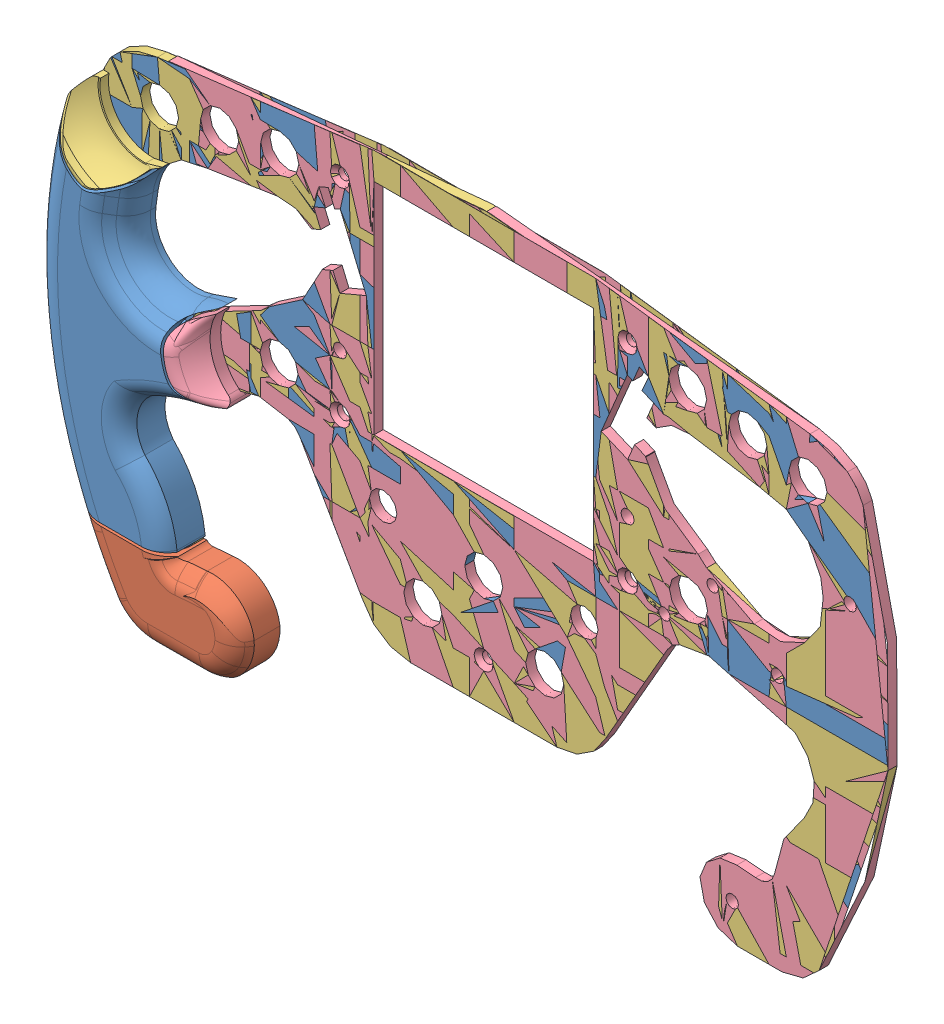
SolidWorks assembly right grip assembly, configuration Default. Lengths in mm.
Overall size (68.83 149.76 15.01).
4 component instances, 4 part files, 9 mates.
Components (placement in the parent):
- left grip no ends or edges-1: left grip no ends or edges [Default] at (82.6904 40.4146 11.7802) size (272.22 167.67 14.17)
- bottom end-1: bottom end [Default] at (82.6904 40.4146 11.7802) size (55.53 45.36 15)
- top end-1: top end [Default] at (82.6904 40.4146 11.7802) size (267.09 167.67 14.23)
- middle end-1: middle end [Default] at (82.6904 40.4146 11.7802) size (236.96 167.67 14.21)
Mates (geometry in assembly coordinates):
- Coincident1: coincident aligned: plane of left grip no ends or edges-1 through (82.6904 40.4146 11.7802) normal (0 0 -1); plane of bottom end-1 through (82.6904 40.4146 11.7802) normal (0 0 -1)
- Coincident2: coincident aligned: plane of left grip no ends or edges-1 through (82.6904 40.4146 11.7802) normal (0 0 -1); plane of top end-1 through (82.6904 40.4146 11.7802) normal (0 0 -1)
- Parallel1: parallel aligned: line of left grip no ends or edges-1 through (-16.1425 -18.1674 25.2802) axis (-1 0 0); line of bottom end-1 through (-16.0263 -19.0674 25.2802) axis (-1 0 0)
- Concentric3: concentric aligned: cylinder of left grip no ends or edges-1 through (116.1065 46.6634 26.7802) axis (0 0 -1) radius 169.0986; cylinder of bottom end-1 through (116.1065 46.6634 26.7802) axis (0 0 -1) radius 169.0986
- Concentric5: concentric aligned: cylinder of left grip no ends or edges-1 through (-16.4419 76.0793 26.7802) axis (0 0 -1) radius 33.4055; cylinder of top end-1 through (-16.4419 76.0793 26.7802) axis (0 0 -1) radius 33.4055
- Concentric6: concentric aligned: cylinder of left grip no ends or edges-1 through (116.1065 46.6634 26.7802) axis (0 0 -1) radius 167.5986; cylinder of top end-1 through (116.1065 46.6634 26.7802) axis (0 0 -1) radius 167.5986
- Parallel2: parallel: face of left grip no ends or edges-1; face of middle end-1
- Coincident3: coincident aligned: plane of left grip no ends or edges-1 through (82.6904 40.4146 11.7802) normal (0 0 -1); plane of middle end-1 through (82.6904 40.4146 11.7802) normal (0 0 -1)
- Concentric7: concentric aligned: cylinder of left grip no ends or edges-1 through (13.752 -38.0168 26.7802) axis (0 0 -1) radius 67.615; cylinder of middle end-1 through (13.752 -38.0168 26.7802) axis (0 0 -1) radius 67.615
